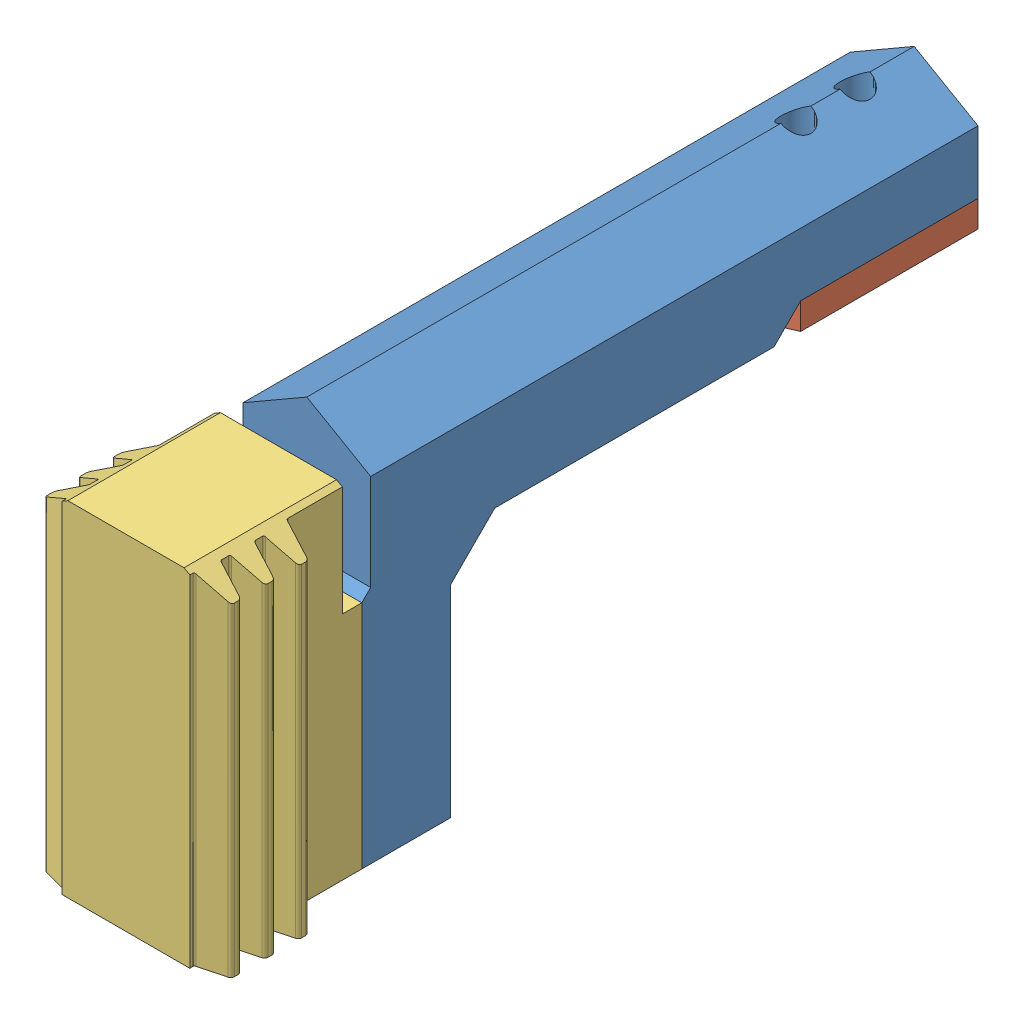
SolidWorks assembly assieme_chela_gommino, configuration Default. Lengths in mm.
Overall size (21.07 42.81 88.9).
7 component instances, 5 part files, 15 mates.
Components (placement in the parent):
- Chela-1: Chela [Default] at (-21.4918 25.3236 31.3) size (14.4 42 72.6)
- Gommino-1: Gommino [Default] at (-21.4918 25.3236 51.3) size (14.4 4.21 20)
- SCHUNK_0303311_PZN_plus_80_1__00000_5-1: SCHUNK_0303311_PZN_plus_80_1__00000_5 [Default] at (-21.4918 20.9689 120.2) x (-1 0 0) z (0 -1 0) size (21.07 19.4 38.8)
- socket head cap screw_iso-5: socket head cap screw_iso [ISO 4762 M5 x 16 - 16N] at (-21.4918 -12.8311 89.8) x (0 0 1) z (0.5 -0.866025 0) size (21 8.5 8.5)
- socket head cap screw_iso-6: socket head cap screw_iso [ISO 4762 M5 x 16 - 16N] at (-21.4918 3.1689 89.8) x (0 0 1) z (-1 0 0) size (21 8.5 8.5)
- socket countersunk head screw_iso-2: socket countersunk head screw_iso [ISO 10642 - M3 x 8 - 8N] at (-21.4918 9.0057 44.6333) x (0 1 0) z (-0.5 0 0.866025) size (8 5.54 5.54)
- socket countersunk head screw_iso-3: socket countersunk head screw_iso [ISO 10642 - M3 x 8 - 8N] at (-21.4918 9.0057 37.9667) x (0 1 0) z (-0.5 0 0.866025) size (8 5.54 5.54)
Mates (geometry in assembly coordinates):
- Coincidente1: coincident anti-aligned: plane of Chela-1 through (-21.4918 12.9236 51.3) normal (0 -1 0); plane of Gommino-1 through (-21.4918 12.9236 31.3) normal (0 1 0)
- Concentrico1: concentric aligned: cylinder of Chela-1 through (-21.4918 12.9236 37.9667) axis (0 -1 0) radius 1.7; cylinder of Gommino-1 through (-21.4918 9.2157 37.9667) axis (0 -1 0) radius 1.7
- Coincidente2: coincident aligned: plane of Chela-1 through (-21.4918 25.3236 31.3) normal (0 0 -1); plane of Gommino-1 through (-21.4918 25.3236 31.3) normal (0 0 -1)
- Coincidente3: coincident anti-aligned: plane of Chela-1 through (-21.4918 25.3236 100.8) normal (0 0 1); plane of SCHUNK_0303311_PZN_plus_80_1__00000_5-1 through (-28.6918 -17.8311 100.8) normal (0 0 -1)
- Parallelo1: parallel anti-aligned: plane of Chela-1 through (-14.2918 -17.8311 90.8) normal (0 -1 0); plane of SCHUNK_0303311_PZN_plus_80_1__00000_5-1 through (-10.9568 8.1689 103) normal (0 1 0)
- Concentrico2: concentric anti-aligned: cylinder of Chela-1 through (-21.4918 3.1689 103.9) axis (0 0 -1) radius 4; cylinder of SCHUNK_0303311_PZN_plus_80_1__00000_5-1 through (-21.4918 3.1689 115.2022) axis (0 0 1) radius 4
- Concentrico5: concentric anti-aligned: cylinder of socket head cap screw_iso-5 through (-21.4918 -12.8311 58.05) axis (0 0 -1) radius 4.25; cylinder of Chela-1 through (-21.4918 -12.8311 31.3) axis (0 0 1) radius 4.5
- Coincidente6: coincident anti-aligned: plane of Chela-1 through (-21.4918 25.3236 94.8) normal (0 0 -1); plane of socket head cap screw_iso-5 through (-25.1724 -14.9561 94.8) normal (0 0 1)
- Concentrico6: concentric anti-aligned: cylinder of Chela-1 through (-21.4918 3.1689 90.8) axis (0 0 1) radius 2.067; cylinder of socket head cap screw_iso-6 through (-21.4918 3.1689 58.05) axis (0 0 -1) radius 4.25
- Coincidente7: coincident anti-aligned: plane of Chela-1 through (-21.4918 25.3236 94.8) normal (0 0 -1); plane of socket head cap screw_iso-6 through (-21.4918 7.4189 94.8) normal (0 0 1)
- Coincidente8: coincident aligned: plane of socket head cap screw_iso-5 through (-23.5338 -14.0101 92.3) normal (1 0 0); plane of socket head cap screw_iso-6 through (-23.5338 1.9899 92.3) normal (1 0 0)
- Perpendicolare1: perpendicular: plane of Chela-1 through (-14.2918 -17.8311 90.8) normal (0 -1 0); plane of socket head cap screw_iso-5 through (-23.5338 -14.0101 92.3) normal (1 0 0)
- Coincidente9: coincident aligned: cone of Gommino-1 through (-21.4918 9.2157 44.6333) axis (0 1 0); cone of socket countersunk head screw_iso-2 through (-21.4918 9.5957 44.6333) axis (0 1 0)
- Coincidente10: coincident aligned: cone of Gommino-1 through (-21.4918 9.2157 37.9667) axis (0 1 0); cone of socket countersunk head screw_iso-3 through (-21.4918 9.5957 37.9667) axis (0 1 0)
- Coincidente11: coincident aligned: plane of socket countersunk head screw_iso-2 through (-20.4918 10.1057 45.2107) normal (-1 0 0); plane of socket countersunk head screw_iso-3 through (-20.4918 10.1057 38.544) normal (-1 0 0)
